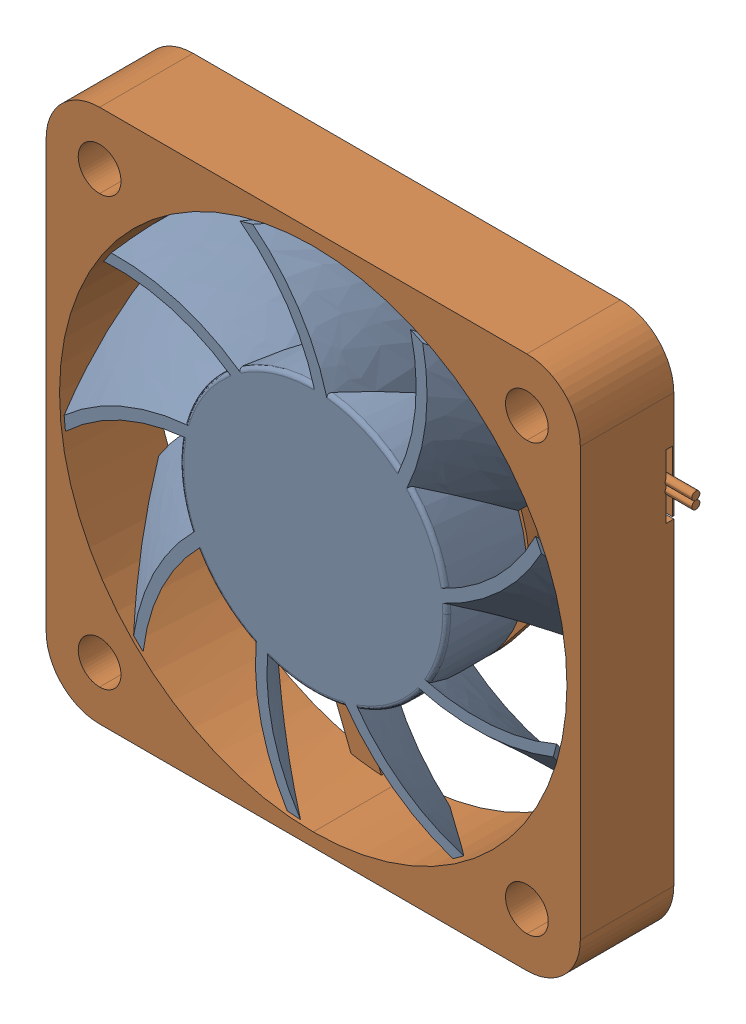
SolidWorks assembly FAN 40x40x7mm, configuration По умолчанию. Lengths in mm.
Overall size (42 40 7).
2 component instances, 2 part files, 0 mates.
Components (placement in the parent):
- Blades-1: Blades [По умолчанию] at (0 0 1) size (37.48 37.48 6.01)
- Housing-1: Housing [По умолчанию] x (0 -1 0) z (0 0 1) size (40 42 7)
